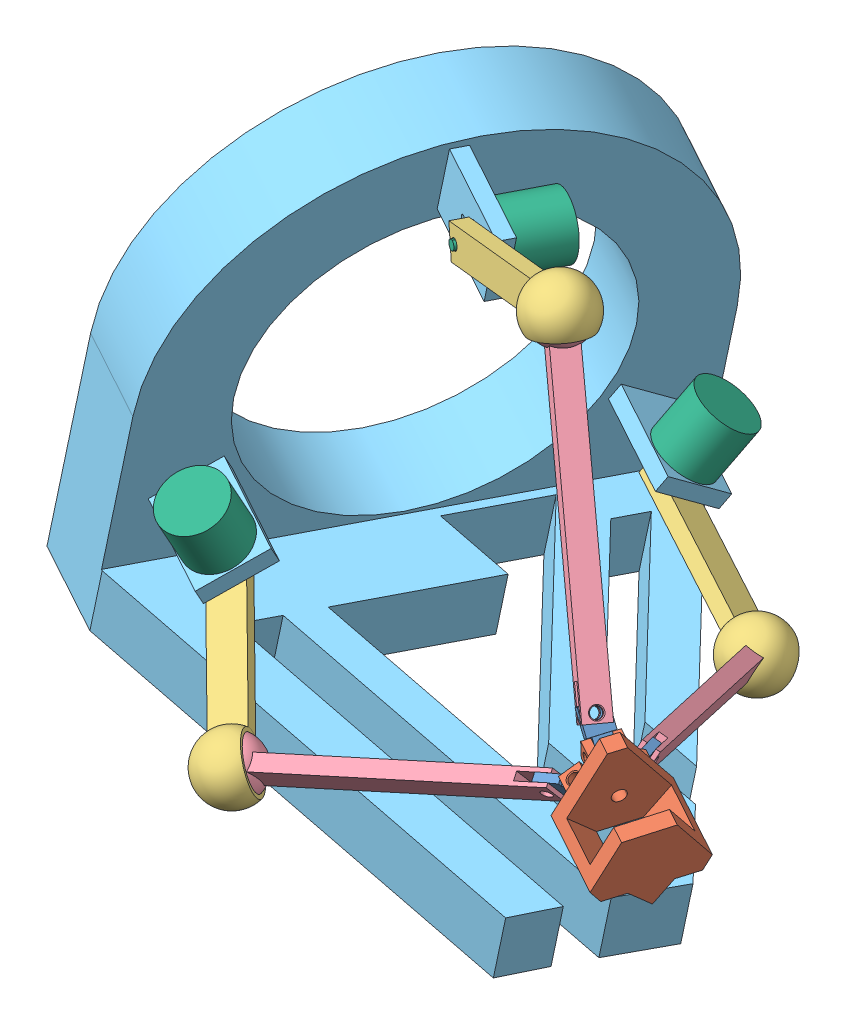
SolidWorks assembly 装配, configuration 默认. Lengths in mm.
Overall size (454.99 376.67 403.55).
14 component instances, 6 part files, 28 mates.
Components (placement in the parent):
- 顶板连接轴-1: 顶板连接轴 [默认] at (511.7677 -194.2094 175.3398) x (-0.550562 0.820587 -0.153359) z (0.418754 0.112552 -0.901098) size (28.88 10 15)
- 顶部板-1: 顶部板 [默认] at (523.5914 -206.2589 182.3833) x (-0.07252 0.782136 0.618873) z (-0.441666 -0.581533 0.683191) size (60 62 51.96)
- 连杆1-1: 连杆1 [默认] at (315.4457 -69.3237 64.4873) x (0.244811 -0.955258 0.165984) z (-0.383907 0.061698 0.921308) size (30.41 140 40)
- 连杆2-1: 连杆2 [默认] at (419.3755 -25.108 106.2313) x (-0.521953 0.056652 0.851091) z (-0.453914 0.82633 -0.333378) size (36 36 208)
- 连杆2-2: 连杆2 [默认] at (316.3247 -278.1969 215.7957) x (-0.137248 0.761721 0.633202) z (-0.928918 -0.320924 0.184716) size (36 36 208)
- 连杆1-2: 连杆1 [默认] at (244.0891 -229.6748 132.5695) x (0.748101 0.318569 -0.582116) z (-0.007314 -0.873217 -0.487277) size (30.41 140 40)
- 顶板连接轴-2: 顶板连接轴 [默认] at (505.6868 -209.8108 180.3611) x (-0.936197 -0.267345 0.228169) z (0.07252 -0.782136 -0.618873) size (28.88 10 15)
- 连杆2-3: 连杆2 [默认] at (426.1844 -275.1587 -14.6187) x (-0.256764 -0.843176 0.472364) z (-0.4439 -0.331261 -0.832598) size (36 36 208)
- 连杆1-3: 连杆1 [默认] at (321.152 -251.8599 -68.696) x (0.207729 -0.537318 -0.817397) z (-0.391222 -0.811519 0.434031) size (30.41 140 40)
- 顶板连接轴-3: 顶板连接轴 [默认] at (513.7972 -215.6348 158.2877) x (-0.378282 -0.142147 -0.914712) z (0.346234 0.894692 -0.282222) size (28.88 10 15)
- 底座-1: 底座 [默认] at (347.7425 -340.3352 75.6752) x (0.383907 -0.061698 -0.921308) z (0.894244 -0.22379 0.387616) size (300 291.88 304.9)
- 编码器-1: 编码器 [默认] at (240.1358 -221.6095 148.8503) x (0.999964 -0.004294 -0.007314) z (0.007314 0.873217 0.487277) size (38 38 55.5)
- 编码器-2: 编码器 [默认] at (322.7848 -59.3055 51.8826) x (-0.866428 -0.369037 -0.336325) z (0.383907 -0.061698 -0.921308) size (38 38 55.5)
- 编码器-3: 编码器 [默认] at (328.9891 -236.4982 -64.733) x (-0.804852 0.073006 -0.588968) z (0.391222 0.811519 -0.434031) size (38 38 55.5)
Mates (geometry in assembly coordinates):
- 同心1: concentric: sphere of 连杆2-1; sphere of 连杆1-1
- 同心2: concentric aligned: cylinder of 顶板连接轴-1 through (501.5441 -179.3799 166.8922) axis (-0.722168 -0.56033 -0.405591) radius 3.3; cone of 连杆2-1 through (506.9604 -175.1774 169.9342) axis (-0.722168 -0.56033 -0.405591)
- 距离2: distance = 0 mm anti-aligned: plane of 顶板连接轴-1 through (505.6588 -171.804 161.4275) normal (0.722168 0.56033 0.405591); plane of 连杆2-1 through (494.4316 -163.7584 170.3027) normal (-0.722168 -0.56033 -0.405591)
- 同心3: concentric anti-aligned: cylinder of 顶板连接轴-1 through (515.9553 -193.0839 166.3288) axis (0.418754 0.112552 -0.901098) radius 3.3; cone of 顶部板-1 through (518.049 -192.5211 161.8233) axis (-0.418754 -0.112552 0.901098)
- 距离3: distance = 0 mm anti-aligned: plane of 顶板连接轴-1 through (511.7677 -194.2094 175.3398) normal (-0.418754 -0.112552 0.901098); plane of 顶部板-1 through (505.0704 -201.0258 171.3761) normal (0.418754 0.112552 -0.901098)
- 同心4: concentric: sphere of 连杆2-2; sphere of 连杆1-2
- 同心5: concentric aligned: cone of 连杆2-2 through (486.4549 -216.0118 177.8651) axis (0.343912 -0.56284 0.751622); cylinder of 顶板连接轴-2 through (489.0343 -220.2331 183.5023) axis (0.343912 -0.56284 0.751622) radius 3.3
- 距离4: distance = 0 mm anti-aligned: plane of 顶板连接轴-2 through (483.3748 -224.5653 176.1954) normal (-0.343912 0.56284 -0.751622); plane of 连杆2-2 through (472.3516 -216.5198 187.2639) normal (0.343912 -0.56284 0.751622)
- 同心7: concentric: sphere of 连杆2-3; sphere of 连杆1-3
- 同心8: concentric aligned: cone of 连杆2-3 through (504.0133 -211.7581 140.8581) axis (0.858502 -0.423463 -0.289229); cylinder of 顶板连接轴-3 through (510.4521 -214.934 138.6888) axis (0.858502 -0.423463 -0.289229) radius 3.3
- 距离6: distance = 0 mm anti-aligned: plane of 顶板连接轴-3 through (506.9446 -206.7873 133.6375) normal (-0.858502 0.423463 0.289229); plane of 连杆2-3 through (497.5753 -224.1094 131.1887) normal (0.858502 -0.423463 -0.289229)
- 距离8: distance = 0.1 mm anti-aligned: plane of 连杆1-1 through (418.8469 -15.8639 99.9649) normal (0.383907 -0.061698 -0.921308); plane of 底座-1 through (275.4525 -322.7598 60.6564) normal (-0.383907 0.061698 0.921308)
- 距离9: distance = 0.1 mm anti-aligned: plane of 底座-1 through (338.6425 -238.3011 -36.3628) normal (-0.391222 -0.811519 0.434031); plane of 连杆1-3 through (426.0632 -265.7279 -8.6149) normal (0.391222 0.811519 -0.434031)
- 同心12: concentric aligned: cylinder of 顶部板-1 through (518.9561 -202.3039 154.0826) axis (0.346234 0.894692 -0.282222) radius 3.3; cylinder of 顶板连接轴-3 through (517.2596 -206.6879 155.4655) axis (0.346234 0.894692 -0.282222) radius 3.3
- 距离10: distance = 0.1 mm anti-aligned: plane of 顶板连接轴-3 through (513.7972 -215.6348 158.2877) normal (-0.346234 -0.894692 0.282222); plane of 顶部板-1 through (502.1594 -205.8799 175.2892) normal (0.346234 0.894692 -0.282222)
- 距离11: distance = 0.1 mm anti-aligned: plane of 底座-1 through (282.143 -212.4306 108.9197) normal (-0.007314 -0.873217 -0.487277); plane of 连杆1-2 through (308.8803 -277.0165 224.0533) normal (0.007314 0.873217 0.487277)
- 同心14: concentric anti-aligned: cylinder of 顶部板-1 through (505.3315 -205.9784 183.3936) axis (-0.07252 0.782136 0.618873) radius 3.3; cylinder of 顶板连接轴-2 through (506.412 -217.6322 174.1724) axis (0.07252 -0.782136 -0.618873) radius 3.3
- 距离12: distance = 0.1 mm anti-aligned: plane of 顶部板-1 through (504.8486 -211.3712 165.9149) normal (-0.07252 0.782136 0.618873); plane of 顶板连接轴-2 through (506.412 -217.6322 174.1724) normal (0.07252 -0.782136 -0.618873)
- 平行1: parallel aligned: plane of 顶部板-1 through (523.5914 -206.2589 182.3833) normal (0.894244 -0.22379 0.387616); plane of 底座-1 through (248.2027 29.7089 172.2282) normal (0.894244 -0.22379 0.387616)
- 同心16: concentric aligned: cylinder of 底座-1 through (318.5618 -58.6269 62.017) axis (0.383907 -0.061698 -0.921308) radius 10.1; cylinder of 编码器-2 through (320.8653 -58.997 56.4891) axis (0.383907 -0.061698 -0.921308) radius 10
- 重合1: coincident anti-aligned: plane of 底座-1 through (279.2916 -323.3768 51.4433) normal (0.383907 -0.061698 -0.921308); plane of 编码器-2 through (322.7848 -59.3055 51.8826) normal (-0.383907 0.061698 0.921308)
- 同心17: concentric aligned: cylinder of 连杆1-1 through (318.9074 -58.6824 61.1878) axis (0.383907 -0.061698 -0.921308) radius 3.3; cylinder of 编码器-2 through (314.5308 -57.979 71.6907) axis (0.383907 -0.061698 -0.921308) radius 3
- 重合2: coincident anti-aligned: plane of 底座-1 through (342.5547 -230.1859 -40.7031) normal (0.391222 0.811519 -0.434031); plane of 编码器-3 through (328.9891 -236.4982 -64.733) normal (-0.391222 -0.811519 0.434031)
- 同心18: concentric aligned: cylinder of 底座-1 through (325.0768 -244.6134 -60.3927) axis (0.391222 0.811519 -0.434031) radius 10.1; cylinder of 编码器-3 through (327.0329 -240.5558 -62.5629) axis (0.391222 0.811519 -0.434031) radius 10
- 同心19: concentric aligned: cylinder of 连杆1-3 through (325.0377 -244.6945 -60.3493) axis (0.391222 0.811519 -0.434031) radius 3.3; cylinder of 编码器-3 through (320.5778 -253.9459 -55.4014) axis (0.391222 0.811519 -0.434031) radius 3
- 重合4: coincident anti-aligned: plane of 底座-1 through (282.2245 -202.7075 114.3454) normal (0.007314 0.873217 0.487277); plane of 编码器-1 through (240.1358 -221.6095 148.8503) normal (-0.007314 -0.873217 -0.487277)
- 同心20: concentric aligned: cylinder of 底座-1 through (239.9676 -241.6935 137.6429) axis (0.007314 0.873217 0.487277) radius 10.1; cylinder of 编码器-1 through (240.0993 -225.9756 146.4139) axis (0.007314 0.873217 0.487277) radius 10
- 同心21: concentric aligned: cylinder of 连杆1-2 through (240.0537 -231.4199 143.3759) axis (0.007314 0.873217 0.487277) radius 3.3; cylinder of 编码器-1 through (239.9786 -240.3837 138.3738) axis (0.007314 0.873217 0.487277) radius 3
